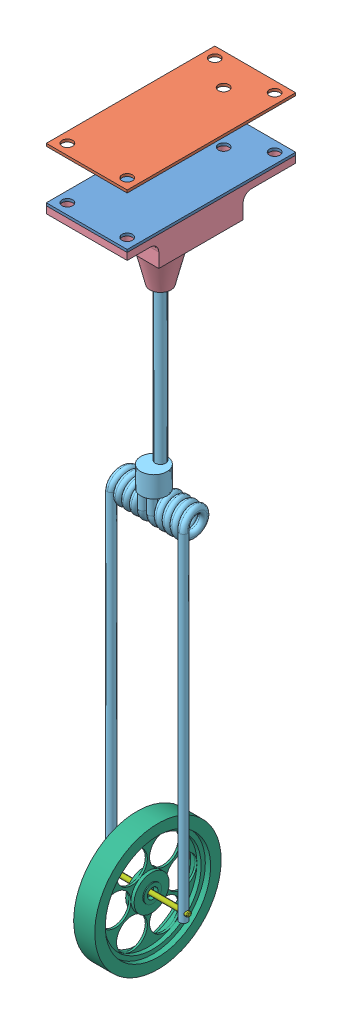
SolidWorks assembly NG_Assembly, configuration Default. Lengths in mm.
Overall size (50.8 434.28 103.12).
7 component instances, 7 part files, 17 mates.
Components (placement in the parent):
- NG_BottomPlate-1: NG_BottomPlate [Default] at origin size (48.77 1.59 101.6)
- NG_TopPlate-1: NG_TopPlate [Default] at (0 31.0515 0) size (48.77 1.59 101.6)
- Shaft_SetScrew_Top-1: Shaft_SetScrew_Top [Default] at (0 -9.525 6.35) x (0.986759 0 0.162195) z (-0.162195 0 0.986759) size (38.1 28.58 38.1)
- NG_UBracket-1: NG_UBracket [Default] at (0 -14.3256 0) size (48.77 50.8 101.6)
- Nose_Gear-1: Nose_Gear [Default] at (0 -155.575 10.3187) size (48.33 358.78 20.71)
- 1.5inWheel-1: 1.5inWheel [Default] at (0 -363.5375 14.22) x (0 0 1) z (-1 0 0) size (76.2 76.2 12.7)
- dowel pin (hardened production)_ai1-1: dowel pin (hardened production)_ai1 [ASME B18.8.2 - 0.1095x2] at (25.4 -363.5375 14.22) x (-1 0 0) z (0 -0.537108 0.843513) size (50.8 2.78 2.78)
Mates (geometry in assembly coordinates):
- Concentric1: concentric aligned: cylinder of NG_TopPlate-1 through (-18.034 32.639 44.45) axis (0 -1 0) radius 3.175; cylinder of NG_BottomPlate-1 through (-18.034 1.5875 44.45) axis (0 -1 0) radius 3.175
- Parallel1: parallel aligned: plane of NG_BottomPlate-1 through (24.384 1.5875 0) normal (1 0 0); plane of NG_TopPlate-1 through (24.384 32.639 -50.8) normal (1 0 0)
- Coincident3: coincident anti-aligned: plane of NG_BottomPlate-1 through (0 0 0) normal (0 -1 0); plane of Shaft_SetScrew_Top-1 through (0 0 6.35) normal (0 1 0)
- Concentric2: concentric anti-aligned: cylinder of NG_BottomPlate-1 through (-18.034 1.5875 44.45) axis (0 -1 0) radius 3.175; cylinder of NG_UBracket-1 through (-18.034 -14.3266 44.45) axis (0 1 0) radius 3.2385
- Parallel2: parallel aligned: plane of NG_BottomPlate-1 through (24.384 1.5875 0) normal (1 0 0); plane of NG_UBracket-1 through (24.384 -14.3256 50.8) normal (1 0 0)
- Concentric3: concentric aligned: cylinder of Shaft_SetScrew_Top-1 through (0 -28.575 6.35) axis (0 1 0) radius 6.35; cylinder of NG_UBracket-1 through (0 -25.5026 6.35) axis (0 1 0) radius 6.4135
- Coincident5: coincident anti-aligned: plane of Shaft_SetScrew_Top-1 through (0 -9.525 6.35) normal (0 -1 0); plane of NG_UBracket-1 through (-14.605 -9.525 20.955) normal (0 1 0)
- Distance1: distance = 29.464 mm anti-aligned: plane of NG_TopPlate-1 through (0 31.0515 0) normal (0 -1 0); plane of NG_BottomPlate-1 through (0 1.5875 0) normal (0 1 0)
- Concentric4: concentric anti-aligned: cylinder of Shaft_SetScrew_Top-1 through (0 -28.575 6.35) axis (0 1 0) radius 3.5; cylinder of Nose_Gear-1 through (0 -9.525 6.35) axis (0 -1 0) radius 3.175
- Coincident7: coincident anti-aligned: plane of Shaft_SetScrew_Top-1 through (0 -9.525 6.35) normal (0 -1 0); plane of Nose_Gear-1 through (0 -9.525 6.35) normal (0 1 0)
- Parallel3: parallel aligned: plane of Nose_Gear-1 through (0 -155.575 10.3187) normal (1 0 0)
- Coincident8: coincident anti-aligned: plane of Shaft_SetScrew_Top-1 through (0 -9.525 6.35) normal (0 -1 0); plane of NG_UBracket-1 through (-14.605 -9.525 20.955) normal (0 1 0)
- Parallel4: parallel anti-aligned: plane of 2inWheel-1 through (-2.54 -363.5375 14.22) normal (-1 0 0)
- Concentric5: concentric aligned: cylinder of Nose_Gear-1 through (-24.1629 -363.5375 14.22) axis (1 0 0) radius 1.5875; cylinder of 2inWheel-1 through (-3.175 -363.5375 14.22) axis (1 0 0) radius 3.175
- Coincident9: coincident anti-aligned: plane of 2inWheel-1 through (0 -363.5375 14.22) normal (-1 0 0)
- Concentric7: concentric aligned: cylinder of 1.5inWheel-1 through (-0.635 -363.5375 14.22) axis (1 0 0) radius 1.5875; cylinder of dowel pin (hardened production)_ai-1 through (31.75 -363.5375 14.22) axis (1 0 0) radius 1.3906
- Width1: width anti-aligned: plane of dowel pin (hardened production)_ai-1 through (-25.4 -363.5375 14.22) normal (-1 0 0); plane of dowel pin (hardened production)_ai-1 through (25.4 -364.282 13.7459) normal (1 0 0); plane of 1.5inWheel-1 through (2.54 -363.5375 14.22) normal (1 0 0); plane of 1.5inWheel-1 through (-2.54 -363.5375 14.22) normal (-1 0 0)
